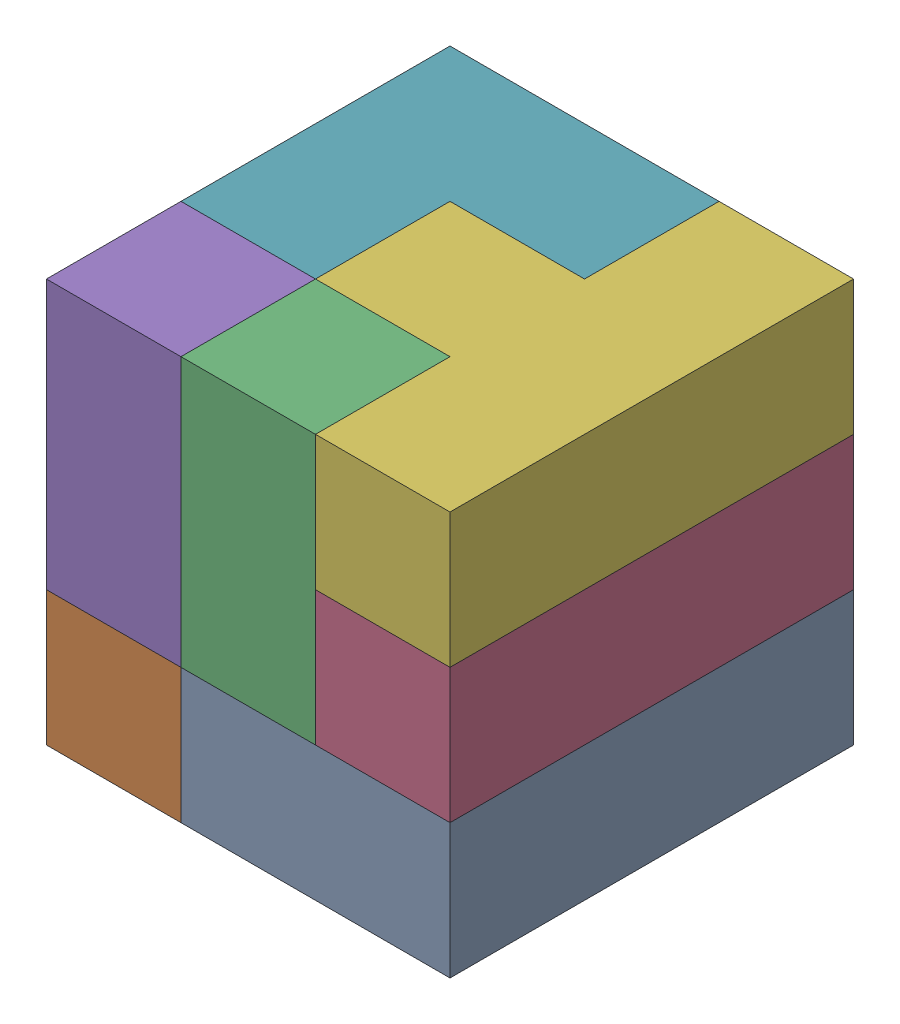
SolidWorks assembly Assem4, configuration Default. Lengths in mm.
Overall size (90 90 90).
10 component instances, 4 part files, 2 mates.
Components (placement in the parent):
- Assem3-1: Assem3 [Default] at (26.0429 -5.6264 9.5826) size (90 30 90)
  - task2Part1-1: task2Part1 [Default] at (54.3963 11.6731 83.9325) x (0 0 -1) z (0 1 0) size (90 60 30)
  - task2Part1-2: task2Part1 [Default] at (-35.6037 11.6731 -6.0675) x (0 0 1) z (0 1 0) size (90 60 30)
- Assem2-1: Assem2 [Default] at (37.5035 -31.8061 48.7347) x (0 1 0) z (1 0 0) size (90 90 90)
  - task2part4-2: task2part4 [Default] at (37.8527 -15.2196 -17.0642) size (90 60 30)
  - task2Part1-2: task2Part1 [Default] at (97.8527 -45.2196 42.9358) x (0 1 0) z (-1 0 0) size (90 60 30)
  - task2Part1-5: task2Part1 [Default] at (67.8527 44.7804 -47.0642) x (0 -1 0) z (0 0 1) size (90 60 30)
- Assem1-2: Assem1 [Default] at (112.2312 -7.1299 78.5468) x (0 0 -1) z (0 1 0) size (90 90 30)
  - task2Part2-1: task2Part2 [Default] at (-14.9683 31.792 73.1766) size (90 60 30)
  - task2Part3-1: task2Part3 [Default] at (75.0317 61.792 73.1766) x (0 1 0) z (0 0 1) size (60 60 30)
Mates (geometry in assembly coordinates):
- Coincident1: coincident: point of Assem3-1/task2Part1-1; point of Assem2-1/task2part4-2
- Coincident3: coincident: point of Assem2-1/task2part4-2; point of Assem1-2/task2Part2-1
